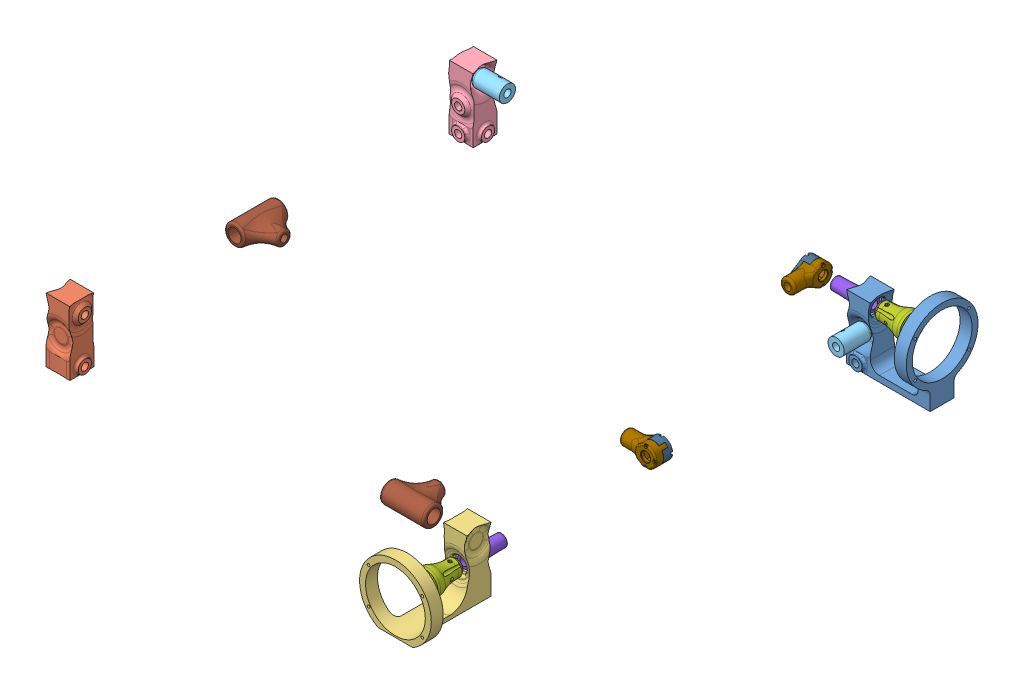
SolidWorks assembly FullSystemAssembly, configuration Default. Lengths in mm.
Overall size (810.33 147.58 854.46).
20 component instances, 11 part files, 36 mates.
Components (placement in the parent):
- cornerPieceXY1WithMotorMount-1: cornerPieceXY1WithMotorMount [Default] at (-4.5523 77.6484 96.7429) size (145 147.58 120)
- cornerPieceForXY3-1: cornerPieceForXY3 [Default] at (-669.0169 77.6484 771.2075) size (47.2 107.08 51.28)
- cornerPieceForXY4withMotorMount-1: cornerPieceForXY4withMotorMount [Default] at (-4.5523 77.6484 811.2075) x (-1 0 0) z (0 0 -1) size (120 112.58 145)
- cornerPieceForXY2-2: cornerPieceForXY2 [Default] at (-669.0169 77.6484 136.7429) x (-1 0 0) z (0 0 -1) size (48.88 107.08 51.28)
- bearingToThreadedRodCouplerLongerV2Part1-1: bearingToThreadedRodCouplerLongerV2Part1 [Default] at (-659.8826 95.1484 116.7429) x (0 0.44584 0.895112) z (1 0 0) size (27 27 58.2)
- bearingToThreadedRodCouplerLongerV2SecondPart-1: bearingToThreadedRodCouplerLongerV2SecondPart [Default] at (-674.8826 95.1484 116.7429) x (0 0.614698 -0.788762) z (0 0.788762 0.614698) size (16 25 16)
- Bearing20ThreadedRodCouplerV2-1: Bearing20ThreadedRodCouplerV2 [Default] at (55.4477 95.1484 116.7429) x (0 -0.153309 0.988178) z (1 0 0) size (42.43 42.43 52.92)
- Bearing20ThreadedRodCoupler-2: Bearing20ThreadedRodCoupler [Default] at (-4.5523 60.1484 699.0732) x (-0.996984 -0.077604 0) z (0 0 -1) size (24 24 63)
- Bearing20ThreadedRodCoupler-3: Bearing20ThreadedRodCoupler [Default] at (-96.6866 95.1484 116.7429) x (0 0.213329 -0.97698) z (-1 0 0) size (24 24 63)
- bearingToThreadedRodCouplerLongerV2Part1-2: bearingToThreadedRodCouplerLongerV2Part1 [Default] at (-4.5523 60.1484 125.8772) x (0.869525 0.493889 0) z (0 0 1) size (27 27 58.2)
- bearingToThreadedRodCouplerLongerV2SecondPart-2: bearingToThreadedRodCouplerLongerV2SecondPart [Default] at (-4.5523 60.1484 110.8772) x (-0.275258 0.961371 0) z (-0.961371 -0.275258 0) size (16 25 16)
- Bearing20ThreadedRodCouplerV2-2: Bearing20ThreadedRodCouplerV2 [Default] at (-4.5523 60.1484 851.2075) x (0.995901 -0.09045 0) z (0 0 1) size (42.43 42.43 52.92)
- ThreadedBarAndNutLinkageAssembled-1: ThreadedBarAndNutLinkageAssembled [Default] at (31.5891 87.2812 539.1583) x (0 -1 0) z (0 0 -1) size (34.1 63.1 28.83)
  - threadedNutAndBarLinkagePart1-1: threadedNutAndBarLinkagePart1 [Default] at (27.1328 36.1413 44.3635) size (34.1 63.1 26.68)
  - threadedNutAndBarLinkagePart2-1: threadedNutAndBarLinkagePart2 [Default] at (27.1328 36.1413 44.5635) size (34.1 55.31 15)
- linearBearingAndBarLinkageWithTwoBearings-1: linearBearingAndBarLinkageWithTwoBearings [Default] at (-669.0169 60.1484 441.7948) x (0 -1 0) z (0 0 1) size (34.1 63.1 74)
- linearBearingAndBarLinkageWithTwoBearings-2: linearBearingAndBarLinkageWithTwoBearings [Default] at (-134.3603 95.1484 791.2075) x (0 -1 0) z (1 0 0) size (34.1 63.1 74)
- ThreadedBarAndNutLinkageAssembled-3: ThreadedBarAndNutLinkageAssembled [Default] at (-36.9968 122.2812 80.6016) x (0 -1 0) z (-1 0 0) size (34.1 63.1 28.83)
  - threadedNutAndBarLinkagePart1-1: threadedNutAndBarLinkagePart1 [Default] at (27.1328 36.1413 44.3635) size (34.1 63.1 26.68)
  - threadedNutAndBarLinkagePart2-1: threadedNutAndBarLinkagePart2 [Default] at (27.1328 36.1413 44.5635) size (34.1 55.31 15)
Mates (geometry in assembly coordinates):
- Parallel2: parallel anti-aligned: plane of cornerPieceXY1WithMotorMount-1 through (-4.5523 77.6484 126.7429) normal (0 0 1); plane of cornerPieceForXY4withMotorMount-1 through (-4.5523 77.6484 781.2075) normal (0 0 -1)
- Parallel5: parallel aligned: plane of cornerPieceForXY3-1 through (-669.0169 7.6484 771.2075) normal (0 -1 0); plane of cornerPieceForXY4withMotorMount-1 through (-4.5523 7.6484 811.2075) normal (0 -1 0)
- Parallel6: parallel aligned: plane of cornerPieceXY1WithMotorMount-1 through (-4.5523 7.6484 96.7429) normal (0 -1 0); plane of cornerPieceForXY4withMotorMount-1 through (-4.5523 7.6484 811.2075) normal (0 -1 0)
- Concentric1: concentric anti-aligned: cylinder of cornerPieceForXY3-1 through (-669.0169 20.1484 751.2075) axis (0 0 1) radius 6.075; cylinder of cornerPieceForXY2-2 through (-669.0169 20.1484 141.7429) axis (0 0 -1) radius 6.075
- Concentric2: concentric aligned: cylinder of cornerPieceXY1WithMotorMount-1 through (-24.5523 20.1484 116.7429) axis (1 0 0) radius 6.075; cylinder of cornerPieceForXY2-2 through (-659.0169 20.1484 116.7429) axis (1 0 0) radius 6.075
- Concentric3: concentric anti-aligned: cylinder of cornerPieceXY1WithMotorMount-1 through (-4.5523 20.1484 136.7429) axis (0 0 -1) radius 6.075; cylinder of cornerPieceForXY4withMotorMount-1 through (-4.5523 20.1484 771.2075) axis (0 0 1) radius 6.075
- Concentric4: concentric anti-aligned: cylinder of cornerPieceForXY3-1 through (-659.0169 20.1484 791.2075) axis (1 0 0) radius 6.075; cylinder of cornerPieceForXY4withMotorMount-1 through (-14.5523 20.1484 791.2075) axis (-1 0 0) radius 6.075
- Coincident11: coincident anti-aligned: circle of bearingToThreadedRodCouplerLongerV2Part1-1; circle of bearingToThreadedRodCouplerLongerV2SecondPart-1
- Concentric11: concentric anti-aligned: cylinder of cornerPieceXY1WithMotorMount-1 through (115.4477 95.1484 116.7429) axis (-1 0 0) radius 50; cylinder of Bearing20ThreadedRodCouplerV2-1 through (24.8111 95.1484 116.7429) axis (1 0 0) radius 21.2132
- Concentric12: concentric anti-aligned: cylinder of cornerPieceForXY4withMotorMount-1 through (-4.5523 60.1484 766.2075) axis (0 0 1) radius 13; cylinder of Bearing20ThreadedRodCoupler-2 through (-4.5523 60.1484 804.0732) axis (0 0 -1) radius 10.05
- Coincident16: coincident aligned: circle of cornerPieceXY1WithMotorMount-1; plane of Bearing20ThreadedRodCoupler-3 through (1.3134 106.8722 119.3028) normal (1 0 0)
- Concentric14: concentric anti-aligned: cylinder of cornerPieceXY1WithMotorMount-1 through (-4.5523 60.1484 146.7429) axis (0 0 -1) radius 16.075; cylinder of bearingToThreadedRodCouplerLongerV2Part1-2 through (-4.5523 60.1484 110.8772) axis (0 0 1) radius 6.05
- Coincident18: coincident anti-aligned: circle of bearingToThreadedRodCouplerLongerV2Part1-2; circle of bearingToThreadedRodCouplerLongerV2SecondPart-2
- Concentric16: concentric anti-aligned: cylinder of Bearing20ThreadedRodCoupler-2 through (-4.5523 60.1484 804.0732) axis (0 0 -1) radius 6.25; cylinder of Bearing20ThreadedRodCouplerV2-2 through (-4.5523 60.1484 746.2075) axis (0 0 1) radius 6.25
- Distance2: distance = 50 mm aligned: plane of Bearing20ThreadedRodCouplerV2-2 through (-4.5523 60.1484 861.2075) normal (0 0 1); plane of cornerPieceForXY4withMotorMount-1 through (-4.5523 77.6484 911.2075) normal (0 0 1)
- Coincident21: coincident aligned: circle of cornerPieceForXY4withMotorMount-1; plane of Bearing20ThreadedRodCoupler-2 through (-3.621 48.1846 797.0732) normal (0 0 1)
- Distance5: distance = 50 mm aligned: plane of Bearing20ThreadedRodCouplerV2-1 through (65.4477 95.1484 116.7429) normal (1 0 0); plane of cornerPieceXY1WithMotorMount-1 through (115.4477 77.6484 96.7429) normal (1 0 0)
- Coincident26: coincident anti-aligned: plane of cornerPieceXY1WithMotorMount-1 through (-4.5523 60.1484 110.8772) normal (0 0 1); circle of bearingToThreadedRodCouplerLongerV2SecondPart-2
- Concentric17: concentric anti-aligned: circle of cornerPieceForXY4withMotorMount-1; circle of Bearing20ThreadedRodCoupler-2
- Concentric18: concentric aligned: circle of cornerPieceForXY2-2; circle of bearingToThreadedRodCouplerLongerV2SecondPart-1
- Coincident27: coincident aligned: plane of cornerPieceForXY2-2 through (-674.8826 77.6484 136.7429) normal (1 0 0); plane of bearingToThreadedRodCouplerLongerV2SecondPart-1 through (-674.8826 95.1484 116.7429) normal (1 0 0)
- Concentric19: concentric anti-aligned: cylinder of cornerPieceXY1WithMotorMount-1 through (-34.5523 95.1484 116.7429) axis (1 0 0) radius 16.075; cylinder of Bearing20ThreadedRodCoupler-3 through (8.3134 95.1484 116.7429) axis (-1 0 0) radius 10.05
- Concentric22: concentric aligned: cylinder of Bearing20ThreadedRodCoupler-2 through (-4.5523 60.1484 804.0732) axis (0 0 -1) radius 6.25; cylinder of ThreadedBarAndNutLinkageAssembled-1/threadedNutAndBarLinkagePart1-1 through (-4.5523 60.1484 492.7948) axis (0 0 -1) radius 7.5
- Concentric23: concentric aligned: cylinder of cornerPieceForXY3-1 through (-669.0169 60.1484 796.2075) axis (0 0 -1) radius 6.075; cylinder of linearBearingAndBarLinkageWithTwoBearings-1 through (-669.0169 60.1484 515.7948) axis (0 0 -1) radius 11.05
- Concentric24: concentric anti-aligned: cylinder of cornerPieceForXY2-2 through (-669.0169 60.1484 111.7429) axis (0 0 1) radius 6.075; cylinder of linearBearingAndBarLinkageWithTwoBearings-1 through (-669.0169 60.1484 515.7948) axis (0 0 -1) radius 11.05
- Concentric25: concentric aligned: cylinder of ThreadedBarAndNutLinkageAssembled-1/threadedNutAndBarLinkagePart1-1 through (-0.6619 60.1484 478.7948) axis (-1 0 0) radius 6.075; cylinder of linearBearingAndBarLinkageWithTwoBearings-1 through (-622.9669 60.1484 478.7948) axis (-1 0 0) radius 6.075
- Concentric26: concentric anti-aligned: cylinder of cornerPieceForXY3-1 through (-674.0169 95.1484 791.2075) axis (1 0 0) radius 6.075; cylinder of cornerPieceForXY4withMotorMount-1 through (0.4477 95.1484 791.2075) axis (-1 0 0) radius 6.075
- Concentric27: concentric aligned: cylinder of cornerPieceForXY3-1 through (-669.0169 60.1484 796.2075) axis (0 0 -1) radius 6.075; cylinder of linearBearingAndBarLinkageWithTwoBearings-1 through (-669.0169 60.1484 515.7948) axis (0 0 -1) radius 11.05
- Distance7: distance = 560 mm anti-aligned: plane of Bearing20ThreadedRodCoupler-2 through (-4.5523 60.1484 734.0772) normal (0 0 -1); plane of bearingToThreadedRodCouplerLongerV2Part1-2 through (-4.5523 60.1484 174.0772) normal (0 0 1)
- Distance8: distance = 550 mm anti-aligned: plane of bearingToThreadedRodCouplerLongerV2Part1-1 through (-611.6826 95.1484 116.7429) normal (1 0 0); plane of Bearing20ThreadedRodCoupler-3 through (-61.6826 95.1484 116.7429) normal (-1 0 0)
- Concentric28: concentric anti-aligned: cylinder of cornerPieceForXY3-1 through (-674.0169 95.1484 791.2075) axis (1 0 0) radius 6.075; cylinder of linearBearingAndBarLinkageWithTwoBearings-2 through (-60.3603 95.1484 791.2075) axis (-1 0 0) radius 11.05
- Concentric29: concentric aligned: cylinder of cornerPieceForXY4withMotorMount-1 through (0.4477 95.1484 791.2075) axis (-1 0 0) radius 6.075; cylinder of linearBearingAndBarLinkageWithTwoBearings-2 through (-60.3603 95.1484 791.2075) axis (-1 0 0) radius 11.05
- Concentric32: concentric aligned: cylinder of bearingToThreadedRodCouplerLongerV2Part1-1 through (-659.8826 95.1484 116.7429) axis (1 0 0) radius 5.995; cylinder of ThreadedBarAndNutLinkageAssembled-3/threadedNutAndBarLinkagePart2-1 through (-116.5603 95.1484 116.7429) axis (1 0 0) radius 7.5
- Concentric33: concentric aligned: cylinder of Bearing20ThreadedRodCoupler-3 through (8.3134 95.1484 116.7429) axis (-1 0 0) radius 6.25; cylinder of ThreadedBarAndNutLinkageAssembled-3/threadedNutAndBarLinkagePart1-1 through (-83.3603 95.1484 116.7429) axis (-1 0 0) radius 7.5
- Concentric34: concentric aligned: cylinder of linearBearingAndBarLinkageWithTwoBearings-2 through (-97.3603 95.1484 745.1575) axis (0 0 1) radius 6.075; cylinder of ThreadedBarAndNutLinkageAssembled-3/threadedNutAndBarLinkagePart1-1 through (-97.3603 95.1484 112.8525) axis (0 0 1) radius 6.075
- Parallel8: parallel anti-aligned: cylinder of Bearing20ThreadedRodCoupler-3 through (8.3134 95.1484 116.7429) axis (-1 0 0) radius 6.25; cylinder of ThreadedBarAndNutLinkageAssembled-3/threadedNutAndBarLinkagePart2-1 through (-116.5603 95.1484 116.7429) axis (1 0 0) radius 7.5
